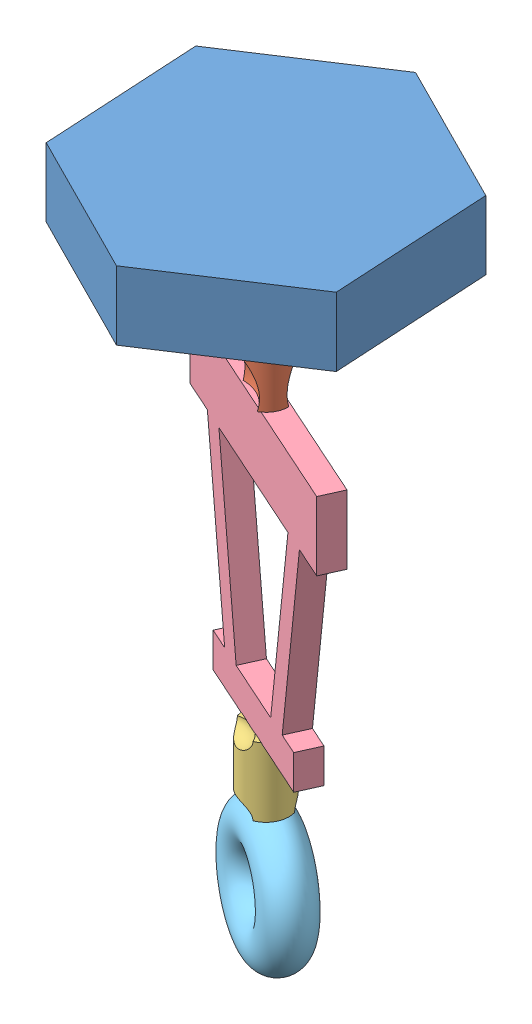
SolidWorks assembly Assem1, configuration Default. Lengths in mm.
Overall size (157.12 383.62 175.7).
5 component instances, 5 part files, 4 mates.
Components (placement in the parent):
- Bent base-1: Bent base [Default] at (-82.3715 -4.726 33.7348) size (157.12 38.1 175.7)
- Bent neck-1: Bent neck [Default] at (-82.3715 -74.4134 33.7348) x (0.859068 0 0.511862) z (0 -1 0) size (25.4 25.4 103.22)
- Bent connector-1: Bent connector [Default] at (-82.405 -271.2694 33.7026) x (-0.435688 0 0.900098) z (-0.900098 0 -0.435688) size (25.4 39.23 25.4)
- Bent main part-1: Bent main part [Default] at (-82.8573 -74.6327 40.2248) x (0.912118 0 0.409929) z (0 1 0) size (139.7 12.7 158.75)
- Bent top-1: Bent top [Default] at (-83.8481 -334.3372 32.858) x (-0.460177 0.032547 0.887231) z (-0.884052 0.075267 -0.461289) size (25.4 76.2 76.2)
Mates (geometry in assembly coordinates):
- Parallel1: parallel anti-aligned: plane of Bent base-1 through (-82.3715 7.974 33.7348) normal (0 -1 0); plane of Bent neck-1 through (-82.3715 27.1866 33.7348) normal (0 1 0)
- Concentric1: concentric aligned: cylinder of Bent base-1 through (-82.3715 7.974 33.7348) axis (0 -1 0) radius 12.7; cylinder of Bent neck-1 through (-82.3715 -74.4134 33.7348) axis (0 -1 0) radius 12.7
- Parallel6: parallel anti-aligned: plane of Bent connector-1 through (-82.405 -233.1694 33.7026) normal (0 1 0); plane of Bent main part-1 through (-118.1948 -233.3827 10.4196) normal (0 -1 0)
- Parallel8: parallel anti-aligned: plane of Bent neck-1 through (-71.4614 -74.4134 40.2354) normal (0 -1 0); plane of Bent main part-1 through (-141.3626 -74.6327 0.0074) normal (0 1 0)
